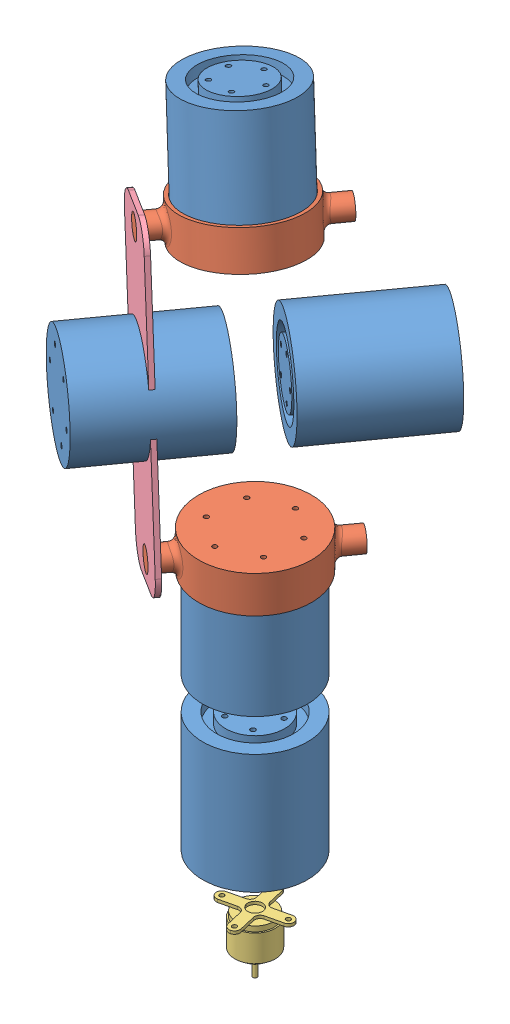
SolidWorks assembly EsambleV1Cuadrupedo, configuration Predeterminado. Lengths in mm.
Overall size (179.98 501.71 204.41).
9 component instances, 4 part files, 13 mates.
Components (placement in the parent):
- Actuador-1: Actuador [Predeterminado] at origin size (71 81 71)
- SoporteMotor1-1: SoporteMotor1 [Predeterminado] at (0 73.5 0) x (-0.583805 0 0.811894) z (0 -1 0) size (106.5 76.5 25)
- Actuador-2: Actuador [Predeterminado] at (0 -22.2123 0) x (-0.857834 0 -0.513927) z (-0.513927 0 0.857834) size (71 81 71)
- Actuador-3: Actuador [Predeterminado] at (-5.8666 160.3105 -26.2047) x (0.777079 -0.289695 0.558771) z (0.235201 0.957119 0.169125) size (71 81 71)
- brushless A2212-1: brushless A2212 [Predeterminado] at (0 -142.5422 0) x (-0.973676 0 0.227938) z (0.227938 0 0.973676) size (45 40.5 45)
- Soporte Exterior de cadera-1: Soporte Exterior de cadera [Predeterminado] at (-43.8874 159.3564 32.1203) x (0.583805 0 -0.811894) z (0.156625 -0.981216 0.112624) size (3.1 60 200)
- SoporteMotor1-2: SoporteMotor1 [Predeterminado] at (-27.4094 245.2128 -19.7092) x (-0.583805 0 0.811894) z (-0.134269 0.98623 -0.096548) size (106.5 76.5 25)
- Actuador-4: Actuador [Predeterminado] at (-37.2782 317.7007 -26.8055) x (-0.732986 -0.16441 -0.660076) z (-0.666861 -0.017859 0.744969) size (71 81 71)
- Actuador-5: Actuador [Predeterminado] at (-22.9422 160.3105 -2.4578) x (-0.107781 -0.991149 -0.077501) z (-0.804708 0.132752 -0.578638) size (71 81 71)
Mates (geometry in assembly coordinates):
- Concéntrica1: concentric anti-aligned: circle of Actuador-1; circle of SoporteMotor1-1
- Coincidente1: coincident anti-aligned: plane of Actuador-1 through (0 81 0) normal (0 1 0); plane of SoporteMotor1-1 through (0 81 0) normal (0 -1 0)
- Concéntrica2: concentric anti-aligned: circle of Actuador-1; circle of Actuador-2
- Concéntrica3: concentric anti-aligned: cylinder of Actuador-2 through (0 -103.2123 0) axis (0 1 0) radius 35.5; circle of brushless A2212-1
- Concéntrica4: concentric aligned: circle of SoporteMotor1-1; circle of Soporte Exterior de cadera-1
- Coincidente3: coincident aligned: plane of SoporteMotor1-1 through (-31.0876 73.5 43.2334) normal (-0.583805 0 0.811894); plane of Soporte Exterior de cadera-1 through (-44.7923 159.3564 33.3788) normal (-0.583805 0 0.811894)
- Concéntrica5: concentric aligned: circle of Soporte Exterior de cadera-1; circle of SoporteMotor1-2
- Coincidente5: coincident aligned: plane of Soporte Exterior de cadera-1 through (-44.7923 159.3564 33.3788) normal (-0.583805 0 0.811894); plane of SoporteMotor1-2 through (-58.497 245.2128 23.5242) normal (-0.583805 0 0.811894)
- Concéntrica6: concentric anti-aligned: circle of SoporteMotor1-2; circle of Actuador-4
- Coincidente6: coincident anti-aligned: plane of SoporteMotor1-2 through (-26.4024 237.816 -18.9851) normal (-0.134269 0.98623 -0.096548); plane of Actuador-4 through (-26.4024 237.816 -18.9851) normal (0.134269 -0.98623 0.096548)
- Concéntrica7: concentric anti-aligned: circle of Actuador-3; circle of SoporteMotor1-2
- Concéntrica8: concentric anti-aligned: circle of SoporteMotor1-1; circle of Actuador-5
- Concéntrica9: concentric anti-aligned: circle of Actuador-3; circle of Actuador-5
